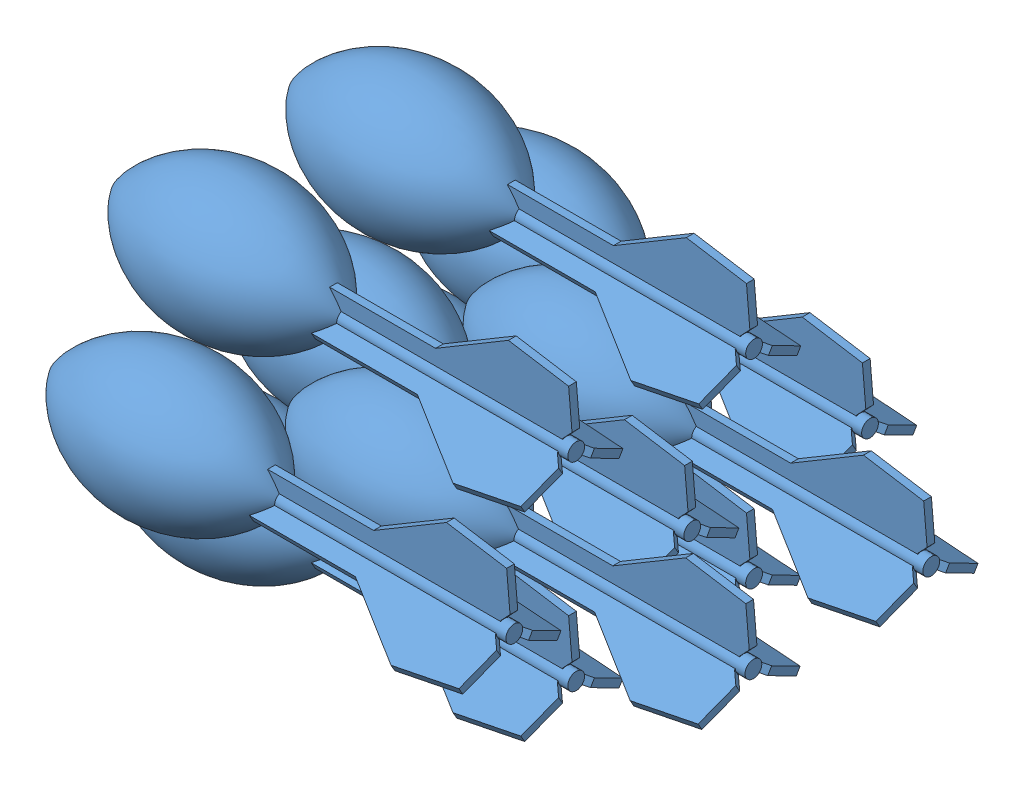
SolidWorks assembly 5 Football Layout, configuration Default. Lengths in mm.
Overall size (421.98 219.96 323.47).
22 component instances, 1 part files, 70 mates.
Components (placement in the parent):
- Habitat-39: Habitat [Default] at (63.8017 231.4109 497.8806) (suppressed, hidden)
- Habitat-40: Habitat [Default] at (-42.7359 231.4109 439.3197)
- Habitat-41: Habitat [Default] at (63.8017 231.4109 380.6103) (suppressed, hidden)
- Habitat-42: Habitat [Default] at (-42.7359 231.4109 322.0494)
- Habitat-43: Habitat [Default] at (63.8017 231.4109 263.3863) (suppressed, hidden)
- Habitat-44: Habitat [Default] at (261.2704 251.8161 439.2455) x (1 -0.000016 0) z (0 0 1) (suppressed, hidden)
- Habitat-45: Habitat [Default] at (261.2704 251.8161 322.0214) x (1 -0.000016 0) z (0 0 1) (suppressed, hidden)
- Habitat-46: Habitat [Default] at (368.9446 251.8144 497.8806) x (1 -0.000016 0) z (0 0 1) (suppressed, hidden)
- Habitat-47: Habitat [Default] at (368.9446 251.8144 380.6103) x (1 -0.000016 0) z (0 0 1) (suppressed, hidden)
- Habitat-48: Habitat [Default] at (368.9446 251.8144 263.3863) x (1 -0.000016 0) z (0 0 1) (suppressed, hidden)
- Habitat-49: Habitat [Default] at (172.4361 231.4109 556.4416) (suppressed, hidden)
- Habitat-50: Habitat [Default] at (172.4361 231.4109 204.3824) (suppressed, hidden)
- Habitat-51: Habitat [Default] at (172.4361 231.4109 321.7202) (suppressed, hidden)
- Habitat-52: Habitat [Default] at (-42.7359 231.4109 204.3824) (suppressed, hidden)
- Habitat-53: Habitat [Default] at (-42.7359 231.4109 556.4416) (suppressed, hidden)
- Habitat-54: Habitat [Default] at (-24.9559 165.6249 380.6103)
- Habitat-56: Habitat [Default] at (-24.9559 165.6249 497.9583)
- Habitat-58: Habitat [Default] at (-24.9559 165.6249 263.3863)
- Habitat-64: Habitat [Default] at (74.1041 165.6249 439.3197)
- Habitat-66: Habitat [Default] at (74.1041 165.6249 322.0494)
- Habitat-68: Habitat [Default] at (-42.7359 100.3469 439.3197)
- Habitat-70: Habitat [Default] at (-42.7359 100.3469 322.0494)
Mates (geometry in assembly coordinates):
- Parallel1: parallel aligned: plane of Habitat-39 through (63.8017 231.4109 500.4206) normal (0 0 1)
- Parallel2: parallel aligned: plane of Habitat-39 through (63.8017 231.4109 497.8806) normal (0 1 0)
- Coincident1: coincident aligned: plane of Habitat-1 through (63.8017 231.4109 497.8806) normal (0 1 0); plane of Habitat-2 through (-42.7359 231.4109 439.3197) normal (0 1 0)
- Parallel3: parallel aligned: plane of Habitat-2 through (-42.7359 231.4109 441.8597) normal (0 0 1)
- Tangent3: tangent anti-aligned: torus of Habitat-1; line of Habitat-2 through (-50.4755 226.0065 453.7604) axis (1 0 0)
- Parallel4: parallel aligned: plane of Habitat-3 through (63.8017 231.4109 383.1503) normal (0 0 1)
- Coincident2: coincident aligned: plane of Habitat-1 through (63.8017 231.4109 497.8806) normal (0 1 0); plane of Habitat-3 through (63.8017 231.4109 380.6103) normal (0 1 0)
- Coincident3: coincident aligned: plane of Habitat-1 through (63.8017 231.4109 497.8806) normal (1 0 0); plane of Habitat-3 through (63.8017 231.4109 380.6103) normal (1 0 0)
- Tangent5: tangent: line of Habitat-2 through (-50.0695 225.9143 424.7191) axis (1 0 0); torus of Habitat-3
- Coincident4: coincident aligned: plane of Habitat-2 through (-42.7359 231.4109 439.3197) normal (0 1 0); plane of Habitat-4 through (-42.7359 231.4109 322.0494) normal (0 1 0)
- Coincident5: coincident aligned: plane of Habitat-2 through (-42.7359 231.4109 439.3197) normal (1 0 0); plane of Habitat-4 through (-42.7359 231.4109 322.0494) normal (1 0 0)
- Distance1: distance = 106.1249 mm aligned: plane of Habitat-2 through (109.3085 244.8341 441.8597) normal (0.996126 0.087943 0); plane of Habitat-1 through (215.8462 244.8341 500.4206) normal (0.996126 0.087943 0)
- Parallel6: parallel aligned: plane of Habitat-5 through (63.8017 231.4109 265.9263) normal (0 0 1)
- Coincident9: coincident aligned: plane of Habitat-3 through (63.8017 231.4109 380.6103) normal (0 1 0); plane of Habitat-5 through (63.8017 231.4109 263.3863) normal (0 1 0)
- Coincident11: coincident aligned: plane of Habitat-3 through (63.8017 231.4109 380.6103) normal (1 0 0); plane of Habitat-5 through (63.8017 231.4109 263.3863) normal (1 0 0)
- Tangent10: tangent anti-aligned: torus of Habitat-5; line of Habitat-4 through (-50.0695 221.5148 309.9889) axis (0 0.866025 -0.5)
- Parallel7: parallel aligned: plane of Habitat-44 through (261.2704 251.8161 441.7855) normal (0 0 1)
- Tangent15: tangent anti-aligned: plane of Habitat-3 through (63.8017 233.6106 381.8803) normal (0 0.866025 0.5); torus of Habitat-12
- Tangent16: tangent anti-aligned: plane of Habitat-39 through (63.8017 233.6106 496.6106) normal (0 0.866025 -0.5); torus of Habitat-44
- Coincident23: coincident aligned: plane of Habitat-12 through (261.2704 251.8161 439.2455) normal (0.000016 1 0); plane of Habitat-45 through (261.2704 251.8161 322.0214) normal (0.000016 1 0)
- Coincident24: coincident aligned: plane of Habitat-12 through (261.2704 251.8161 439.2455) normal (1 -0.000016 0); plane of Habitat-45 through (261.2704 251.8161 322.0214) normal (1 -0.000016 0)
- Tangent19: tangent anti-aligned: plane of Habitat-5 through (63.8017 233.6106 264.6563) normal (0 0.866025 0.5); torus of Habitat-45
- Coincident35: coincident aligned: plane of Habitat-45 through (261.2704 251.8161 322.0214) normal (0.000016 1 0); plane of Habitat-19 through (368.9446 251.8144 497.8806) normal (0.000016 1 0)
- Parallel15: parallel aligned: plane of Habitat-19 through (368.9446 251.8144 500.4206) normal (0 0 1)
- Coincident37: coincident aligned: plane of Habitat-1 through (63.8017 231.4109 500.4206) normal (0 0 1); plane of Habitat-19 through (368.9446 251.8144 500.4206) normal (0 0 1)
- Distance3: distance = 107.257 mm aligned: plane of Habitat-19 through (520.9892 265.2353 500.4206) normal (0.996127 0.087927 0); plane of Habitat-12 through (413.315 265.237 441.7855) normal (0.996127 0.087927 0)
- Parallel16: parallel aligned: plane of Habitat-20 through (368.9446 251.8144 383.1503) normal (0 0 1)
- Coincident39: coincident aligned: plane of Habitat-19 through (368.9446 251.8144 497.8806) normal (0.000016 1 0); plane of Habitat-20 through (368.9446 251.8144 380.6103) normal (0.000016 1 0)
- Coincident40: coincident aligned: plane of Habitat-19 through (368.9446 251.8144 497.8806) normal (1 -0.000016 0); plane of Habitat-20 through (368.9446 251.8144 380.6103) normal (1 -0.000016 0)
- Coincident41: coincident aligned: plane of Habitat-3 through (63.8017 231.4109 383.1503) normal (0 0 1); plane of Habitat-20 through (368.9446 251.8144 383.1503) normal (0 0 1)
- Parallel17: parallel aligned: plane of Habitat-22 through (368.9446 251.8144 265.9263) normal (0 0 1)
- Coincident42: coincident aligned: plane of Habitat-19 through (368.9446 251.8144 497.8806) normal (0.000016 1 0); plane of Habitat-22 through (368.9446 251.8144 263.3863) normal (0.000016 1 0)
- Coincident43: coincident aligned: plane of Habitat-19 through (368.9446 251.8144 497.8806) normal (1 -0.000016 0); plane of Habitat-22 through (368.9446 251.8144 263.3863) normal (1 -0.000016 0)
- Coincident44: coincident aligned: plane of Habitat-5 through (63.8017 231.4109 265.9263) normal (0 0 1); plane of Habitat-22 through (368.9446 251.8144 265.9263) normal (0 0 1)
- Tangent20: tangent: torus of Habitat-3; line of Habitat-4 through (-50.4755 226.0065 336.4901) axis (1 0 0)
- Parallel18: parallel aligned: plane of Habitat-39 through (63.8017 231.4109 500.4206) normal (0 0 1); plane of Habitat-49 through (172.4361 231.4109 558.9816) normal (0 0 1)
- Coincident46: coincident aligned: plane of Habitat-39 through (63.8017 231.4109 497.8806) normal (0 1 0); plane of Habitat-49 through (172.4361 231.4109 556.4416) normal (0 1 0)
- Tangent22: tangent: line of Habitat-39 through (56.0622 226.0065 512.3213) axis (1 0 0); torus of Habitat-49
- Coincident52: coincident: plane of Habitat-49 through (172.4361 231.4109 556.4416) normal (0 1 0); plane of Habitat-51 through (172.4361 231.4109 321.7202) normal (0 1 0)
- Coincident53: coincident: plane of Habitat-49 through (172.4361 231.4109 556.4416) normal (1 0 0); plane of Habitat-51 through (172.4361 231.4109 321.7202) normal (1 0 0)
- Parallel22: parallel aligned: plane of Habitat-3 through (63.8017 231.4109 378.0703) normal (0 0 -1); plane of Habitat-26 through (172.4361 231.4109 319.1802) normal (0 0 -1)
- Coincident56: coincident aligned: plane of Habitat-4 through (-42.7359 231.4109 322.0494) normal (0 1 0); plane of Habitat-28 through (-42.7359 231.4109 204.3824) normal (0 1 0)
- Coincident57: coincident aligned: plane of Habitat-4 through (-42.7359 231.4109 322.0494) normal (1 0 0); plane of Habitat-28 through (-42.7359 231.4109 204.3824) normal (1 0 0)
- Coincident58: coincident aligned: plane of Habitat-25 through (172.4361 231.4109 204.3824) normal (0 0 1); plane of Habitat-28 through (-42.7359 231.4109 204.3824) normal (0 0 1)
- Coincident59: coincident aligned: plane of Habitat-28 through (-42.7359 231.4109 204.3824) normal (0 1 0); plane of Habitat-37 through (-42.7359 231.4109 556.4416) normal (0 1 0)
- Coincident60: coincident aligned: plane of Habitat-4 through (-42.7359 231.4109 322.0494) normal (1 0 0); plane of Habitat-37 through (-42.7359 231.4109 556.4416) normal (1 0 0)
- Coincident61: coincident aligned: plane of Habitat-23 through (172.4361 231.4109 556.4416) normal (0 0 1); plane of Habitat-37 through (-42.7359 231.4109 556.4416) normal (0 0 1)
- Parallel25: parallel aligned: plane of Habitat-54 through (-24.9559 165.6249 380.6103) normal (0 1 0)
- Distance5: distance = 17.78 mm aligned: plane of Habitat-40 through (-94.4759 231.4109 439.3197) normal (1 0 0); plane of Habitat-54 through (-76.6959 165.6249 380.6103) normal (1 0 0)
- Coincident67: coincident aligned: plane of Habitat-41 through (63.8017 231.4109 380.6103) normal (0 0 1); plane of Habitat-54 through (-24.9559 165.6249 380.6103) normal (0 0 1)
- Distance4: distance = 65.786 mm aligned: plane of Habitat-40 through (-42.7359 231.4109 439.3197) normal (0 1 0); plane of Habitat-54 through (-24.9559 165.6249 380.6103) normal (0 1 0)
- Coincident69: coincident aligned: plane of Habitat-54 through (-24.9559 165.6249 380.6103) normal (0 1 0); plane of Habitat-56 through (-24.9559 165.6249 497.9583) normal (0 1 0)
- Coincident70: coincident aligned: plane of Habitat-54 through (-24.9559 165.6249 380.6103) normal (0 1 0); plane of Habitat-56 through (-24.9559 165.6249 497.9583) normal (0 1 0)
- Coincident71: coincident aligned: plane of Habitat-54 through (-24.9559 165.6249 380.6103) normal (1 0 0); plane of Habitat-56 through (-24.9559 165.6249 497.9583) normal (1 0 0)
- Distance6: distance = 117.348 mm aligned: plane of Habitat-54 through (-24.9559 165.6249 380.6103) normal (0 0 1); plane of Habitat-56 through (-24.9559 165.6249 497.9583) normal (0 0 1)
- Coincident73: coincident aligned: plane of Habitat-56 through (-24.9559 165.6249 497.9583) normal (0 1 0); plane of Habitat-58 through (-24.9559 165.6249 263.3863) normal (0 1 0)
- Coincident74: coincident aligned: plane of Habitat-56 through (-24.9559 165.6249 497.9583) normal (1 0 0); plane of Habitat-58 through (-24.9559 165.6249 263.3863) normal (1 0 0)
- Coincident75: coincident aligned: plane of Habitat-43 through (63.8017 231.4109 263.3863) normal (0 0 1); plane of Habitat-58 through (-24.9559 165.6249 263.3863) normal (0 0 1)
- Coincident76: coincident aligned: plane of Habitat-58 through (-24.9559 165.6249 263.3863) normal (0 1 0); plane of Habitat-64 through (74.1041 165.6249 439.3197) normal (0 1 0)
- Coincident77: coincident aligned: plane of Habitat-40 through (-42.7359 231.4109 439.3197) normal (0 0 1); plane of Habitat-64 through (74.1041 165.6249 439.3197) normal (0 0 1)
- Distance7: distance = 99.06 mm aligned: plane of Habitat-64 through (22.3641 165.6249 439.3197) normal (1 0 0); plane of Habitat-56 through (-76.6959 165.6249 497.9583) normal (1 0 0)
- Coincident79: coincident aligned: plane of Habitat-64 through (74.1041 165.6249 439.3197) normal (0 1 0); plane of Habitat-66 through (74.1041 165.6249 322.0494) normal (0 1 0)
- Coincident80: coincident aligned: plane of Habitat-64 through (74.1041 165.6249 439.3197) normal (1 0 0); plane of Habitat-66 through (74.1041 165.6249 322.0494) normal (1 0 0)
- Coincident81: coincident aligned: plane of Habitat-42 through (-42.7359 231.4109 322.0494) normal (0 0 1); plane of Habitat-66 through (74.1041 165.6249 322.0494) normal (0 0 1)
- Coincident82: coincident aligned: plane of Habitat-40 through (-42.7359 231.4109 439.3197) normal (1 0 0); plane of Habitat-68 through (-42.7359 100.3469 439.3197) normal (1 0 0)
- Coincident83: coincident aligned: plane of Habitat-40 through (-42.7359 231.4109 439.3197) normal (0 0 1); plane of Habitat-68 through (-42.7359 100.3469 439.3197) normal (0 0 1)
- Distance8: distance = 65.278 mm aligned: plane of Habitat-68 through (-42.7359 100.3469 439.3197) normal (0 1 0); plane of Habitat-54 through (-24.9559 165.6249 380.6103) normal (0 1 0)
- Coincident85: coincident aligned: plane of Habitat-68 through (-42.7359 100.3469 439.3197) normal (0 1 0); plane of Habitat-70 through (-42.7359 100.3469 322.0494) normal (0 1 0)
- Coincident86: coincident aligned: plane of Habitat-68 through (-42.7359 100.3469 439.3197) normal (1 0 0); plane of Habitat-70 through (-42.7359 100.3469 322.0494) normal (1 0 0)
- Coincident87: coincident aligned: plane of Habitat-42 through (-42.7359 231.4109 322.0494) normal (0 0 1); plane of Habitat-70 through (-42.7359 100.3469 322.0494) normal (0 0 1)
